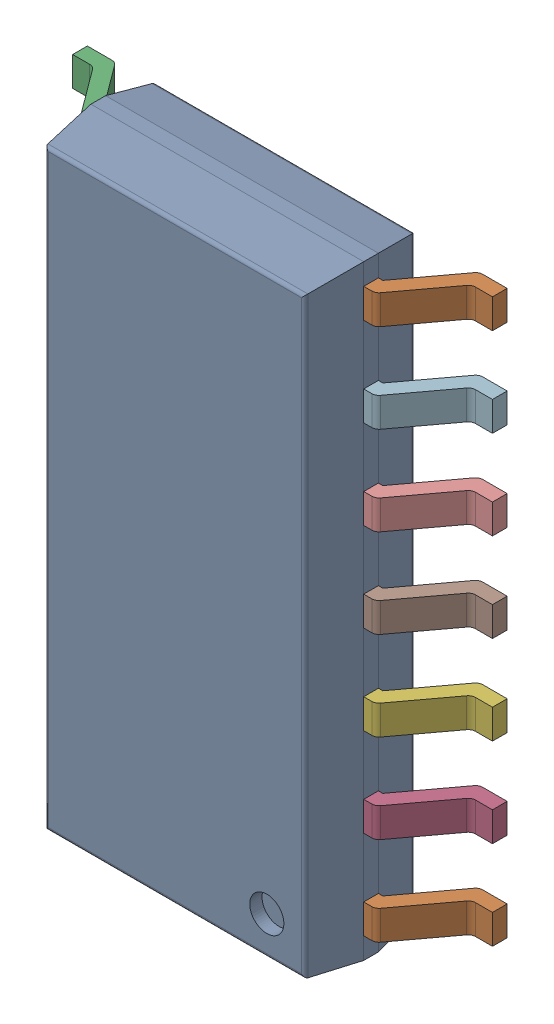
SolidWorks assembly IC11_IC105_1.step, configuration Default. Lengths in mm.
Overall size (6 8.65 1.75).
3 component instances, 2 part files, 0 mates.
Components (placement in the parent):
- 6348793888_1.step-11: 6348793888_1.step [Default] at (343.742 252.954 0) x (-1 0 0) z (0 0 1) size (6 8.65 1.75)
  - Body-16_1.step-54: Body-16_1.step [Default] at origin size (3.9 8.65 1.57)
  - PinsArrayLR-17_1.step-54: PinsArrayLR-17_1.step [Default] at origin size (6 8.04 1)
